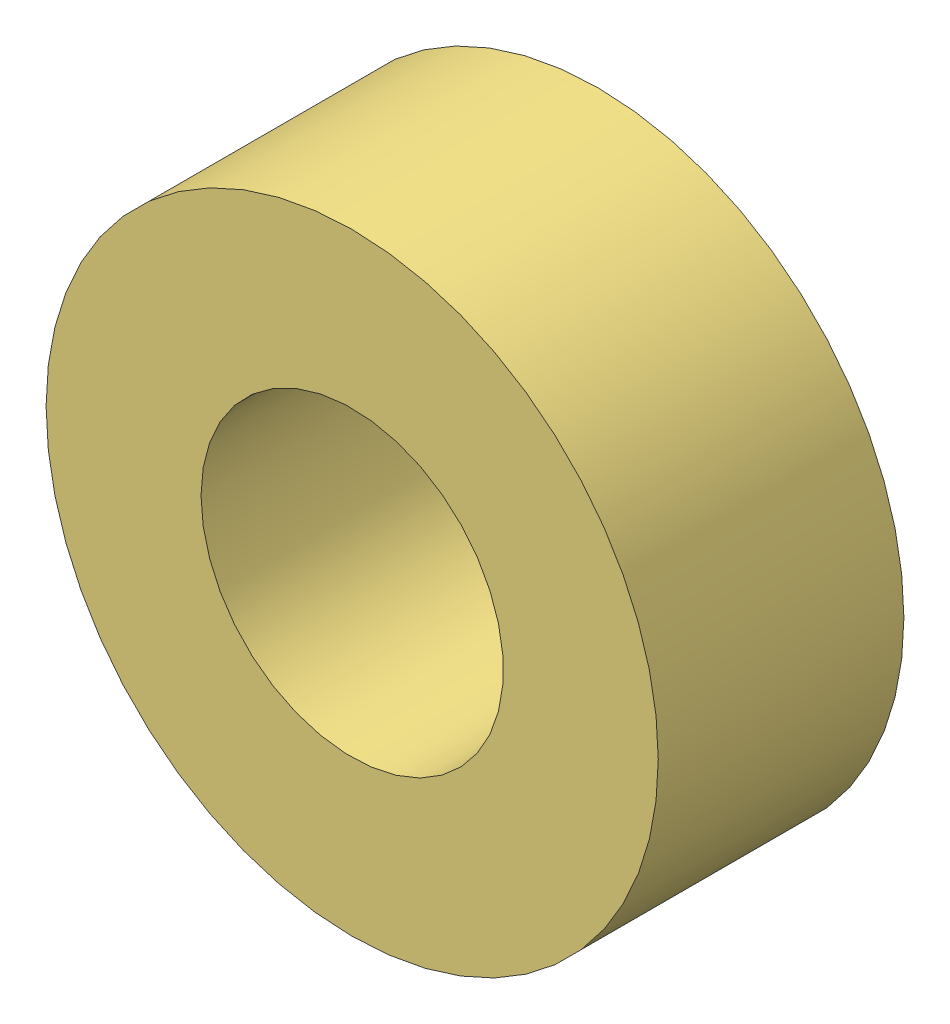
SolidWorks assembly EA2, configuration Default. Lengths in mm.
Overall size (411.48 411.48 213.36).
14 component instances, 5 part files, 31 mates.
Components (placement in the parent):
- EP2-1: EP2 [Default] at (14.289 67.5101 114.1198) size (127 127 48.26)
- hex bolt_ai-1: hex bolt_ai [HBOLT 0.4375-20x1.375x1.125-N] at (-36.511 67.5101 106.0934) x (0 0 1) z (-0.866025 -0.5 0) size (42.95 18.33 15.88)
- hex bolt_ai-2: hex bolt_ai [HBOLT 0.4375-20x1.375x1.125-N] at (14.289 118.3101 106.0934) x (0 0 1) z (0 -1 0) size (42.95 18.33 15.88)
- hex bolt_ai-3: hex bolt_ai [HBOLT 0.4375-20x1.375x1.125-N] at (14.289 16.7101 106.0934) x (0 0 1) z (-0.866025 0.5 0) size (42.95 18.33 15.88)
- hex bolt_ai-4: hex bolt_ai [HBOLT 0.4375-20x1.375x1.125-N] at (65.089 67.5101 106.0934) x (0 0 1) z (-0.866025 0.5 0) size (42.95 18.33 15.88)
- EB2-1: EB2 [Default] at (14.289 67.5101 129.9948) x (-1 0 0) z (0 0 -1) size (411.48 411.48 165.1)
- flat washer type a wide_ai-1: flat washer type a wide_ai [Preferred Wide FW 0.4375] at (-36.511 67.5101 132.103) x (0 0 1) z (-0.923728 -0.383049 0) size (2.11 31.75 31.75)
- flat washer type a wide_ai-2: flat washer type a wide_ai [Preferred Wide FW 0.4375] at (14.289 118.3101 132.103) x (0 0 1) z (1 0 0) size (2.11 31.75 31.75)
- flat washer type a wide_ai-3: flat washer type a wide_ai [Preferred Wide FW 0.4375] at (14.289 16.7101 132.103) x (0 0 1) z (1 0 0) size (2.11 31.75 31.75)
- flat washer type a wide_ai-4: flat washer type a wide_ai [Preferred Wide FW 0.4375] at (65.089 67.5101 132.103) x (0 0 1) z (1 0 0) size (2.11 31.75 31.75)
- hex thick nut_ai-1: hex thick nut_ai [HTNUT 0.4375-14-D-N] at (14.289 16.7101 143.8632) x (0.055202 -0.998475 0) z (0 0 1) size (17.48 20.18 11.76)
- hex thick nut_ai-2: hex thick nut_ai [HTNUT 0.4375-14-D-N] at (-36.511 67.5101 143.8632) x (0.547044 -0.837104 0) z (0 0 1) size (17.48 20.18 11.76)
- hex thick nut_ai-3: hex thick nut_ai [HTNUT 0.4375-14-D-N] at (65.089 67.5101 143.8632) x (-0.982324 -0.18719 0) z (0 0 1) size (17.48 20.18 11.76)
- hex thick nut_ai-4: hex thick nut_ai [HTNUT 0.4375-14-D-N] at (14.289 118.3101 143.8632) x (0.055202 -0.998475 0) z (0 0 1) size (17.48 20.18 11.76)
Mates (geometry in assembly coordinates):
- Concentric3: concentric: cylinder of EP2-1 through (-36.511 67.5101 126.8198) axis (0 0 -1) radius 5.5563; cylinder of hex bolt_ai-1 through (-36.511 67.5101 106.0934) axis (0 0 -1) radius 5.5563
- Coincident6: coincident: plane of EP2-1 through (14.289 67.5101 114.1198) normal (0 0 -1); plane of hex bolt_ai-1 through (-41.0937 75.4476 114.1198) normal (0 0 1)
- Concentric4: concentric: cylinder of EP2-1 through (14.289 118.3101 126.8198) axis (0 0 -1) radius 5.5563; cylinder of hex bolt_ai-2 through (14.289 118.3101 106.0934) axis (0 0 -1) radius 5.5563
- Concentric5: concentric: cylinder of EP2-1 through (65.089 67.5101 126.8198) axis (0 0 -1) radius 5.5563; cylinder of hex bolt_ai-4 through (65.089 67.5101 106.0934) axis (0 0 -1) radius 5.5563
- Concentric6: concentric: cylinder of EP2-1 through (14.289 16.7101 126.8198) axis (0 0 -1) radius 5.5563; cylinder of hex bolt_ai-3 through (14.289 16.7101 106.0934) axis (0 0 -1) radius 5.5563
- Coincident8: coincident: plane of EP2-1 through (14.289 67.5101 114.1198) normal (0 0 -1); plane of hex bolt_ai-4 through (69.6718 75.4476 114.1198) normal (0 0 1)
- Coincident10: coincident: plane of EP2-1 through (14.289 67.5101 114.1198) normal (0 0 -1); plane of hex bolt_ai-3 through (18.8718 24.6476 114.1198) normal (0 0 1)
- Coincident12: coincident: plane of EP2-1 through (14.289 67.5101 114.1198) normal (0 0 -1); plane of hex bolt_ai-2 through (5.1236 118.3101 114.1198) normal (0 0 1)
- Concentric7: concentric: cylinder of EB2-1 through (14.289 16.7101 126.8198) axis (0 0 1) radius 5.5563; cylinder of hex bolt_ai-3 through (14.289 16.7101 106.0934) axis (0 0 -1) radius 5.5563
- Concentric10: concentric: cylinder of hex bolt_ai-1 through (-36.511 67.5101 106.0934) axis (0 0 -1) radius 5.5563; cylinder of EB2-1 through (-36.511 67.5101 126.8198) axis (0 0 1) radius 5.5563
- Coincident14: coincident: plane of EP2-1 through (14.289 67.5101 126.8198) normal (0 0 1); plane of EB2-1 through (14.289 67.5101 126.8198) normal (0 0 -1)
- Concentric11: concentric: cylinder of hex bolt_ai-4 through (65.089 67.5101 106.0934) axis (0 0 -1) radius 5.5563; cylinder of flat washer type a wide_ai-4 through (65.089 67.5101 97.178) axis (0 0 -1) radius 6.35
- Concentric12: concentric: cylinder of hex bolt_ai-2 through (14.289 118.3101 106.0934) axis (0 0 -1) radius 5.5563; cylinder of flat washer type a wide_ai-2 through (14.289 118.3101 97.178) axis (0 0 -1) radius 6.35
- Concentric13: concentric: cylinder of hex bolt_ai-3 through (14.289 16.7101 106.0934) axis (0 0 -1) radius 5.5563; cylinder of flat washer type a wide_ai-3 through (14.289 16.7101 97.178) axis (0 0 -1) radius 6.35
- Concentric14: concentric: circle of hex bolt_ai-1; cylinder of flat washer type a wide_ai-1 through (-36.511 67.5101 97.178) axis (0 0 -1) radius 6.35
- Coincident15: coincident: plane of EB2-1 through (14.289 67.5101 129.9948) normal (0 0 1); plane of flat washer type a wide_ai-2 through (14.289 102.4351 129.9948) normal (0 0 -1)
- Coincident17: coincident: plane of EB2-1 through (14.289 67.5101 129.9948) normal (0 0 1); plane of flat washer type a wide_ai-1 through (-42.5919 82.1743 129.9948) normal (0 0 -1)
- Coincident18: coincident: plane of EB2-1 through (14.289 67.5101 129.9948) normal (0 0 1); plane of flat washer type a wide_ai-4 through (65.089 51.6351 129.9948) normal (0 0 -1)
- Coincident19: coincident: plane of EB2-1 through (14.289 67.5101 129.9948) normal (0 0 1); plane of flat washer type a wide_ai-3 through (14.289 0.8351 129.9948) normal (0 0 -1)
- Concentric15: concentric: cylinder of hex bolt_ai-1 through (-36.511 67.5101 106.0934) axis (0 0 -1) radius 5.5563; cylinder of hex thick nut_ai-2 through (-36.511 67.5101 132.103) axis (0 0 1) radius 4.6736
- Concentric16: concentric: cylinder of hex bolt_ai-3 through (14.289 16.7101 106.0934) axis (0 0 -1) radius 5.5563; cylinder of hex thick nut_ai-1 through (14.289 16.7101 132.103) axis (0 0 1) radius 4.6736
- Concentric17: concentric: cylinder of hex bolt_ai-2 through (14.289 118.3101 106.0934) axis (0 0 -1) radius 5.5563; circle of hex thick nut_ai-4
- Concentric18: concentric: cylinder of hex thick nut_ai-3 through (65.089 67.5101 132.103) axis (0 0 1) radius 4.6736; circle of hex bolt_ai-4
- Coincident21: coincident: plane of flat washer type a wide_ai-3 through (14.289 10.3601 132.103) normal (0 0 1); plane of hex thick nut_ai-1 through (24.363 17.267 132.103) normal (0 0 -1)
- Coincident22: coincident: plane of flat washer type a wide_ai-1 through (-38.9433 73.3758 132.103) normal (0 0 1); plane of hex thick nut_ai-2 through (-28.0652 73.0294 132.103) normal (0 0 -1)
- Coincident23: coincident: plane of flat washer type a wide_ai-4 through (65.089 61.1601 132.103) normal (0 0 1); plane of hex thick nut_ai-3 through (66.9777 57.5991 132.103) normal (0 0 -1)
- Coincident24: coincident: plane of flat washer type a wide_ai-2 through (14.289 111.9601 132.103) normal (0 0 1); plane of hex thick nut_ai-4 through (24.363 118.867 132.103) normal (0 0 -1)
- Parallel1: parallel: line of EP2-1 through (11.9014 72.5739 78.5598) axis (1 0 0); line of hex bolt_ai-1 through (-31.9282 75.4476 114.1198) axis (-1 0 0)
- Parallel2: parallel: line of EP2-1 through (11.9014 72.5739 78.5598) axis (1 0 0); line of hex bolt_ai-3 through (18.8718 24.6476 114.1198) axis (-1 0 0)
- Parallel3: parallel: line of EP2-1 through (11.9014 72.5739 78.5598) axis (1 0 0); line of hex bolt_ai-4 through (69.6718 75.4476 114.1198) axis (-1 0 0)
- Parallel4: parallel: line of EP2-1 through (11.9014 72.5739 78.5598) axis (1 0 0); line of hex bolt_ai-2 through (9.7063 110.3726 114.1198) axis (1 0 0)
